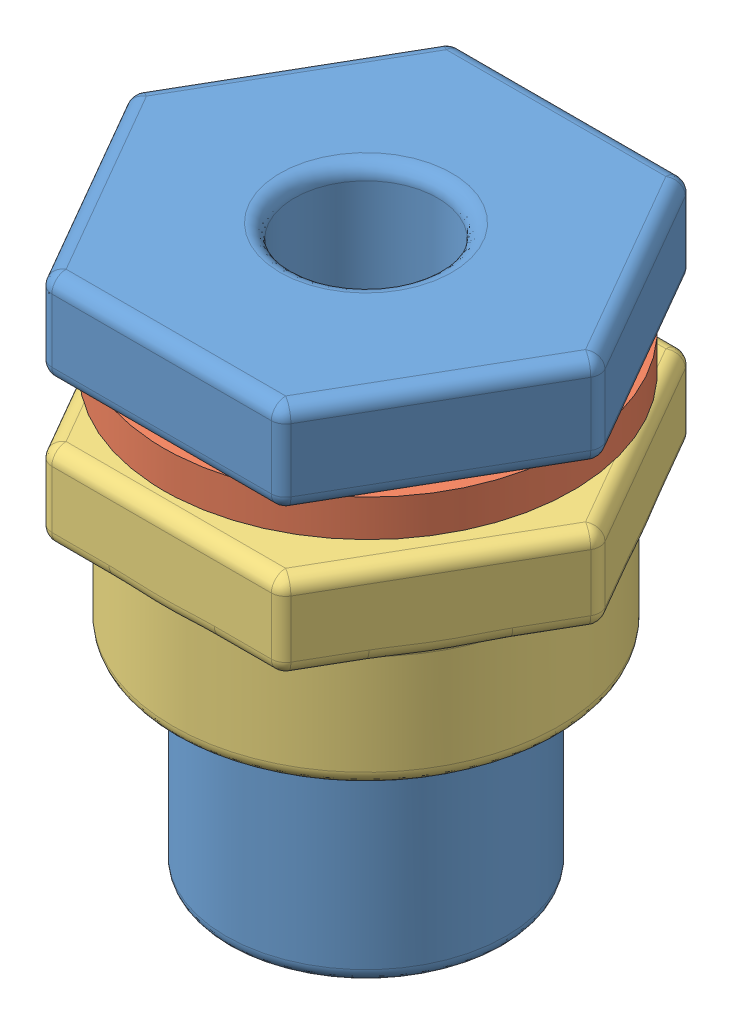
SolidWorks assembly drain_assembly, configuration Default. Lengths in mm.
Overall size (58.27 70.14 50.8).
3 component instances, 3 part files, 4 mates.
Components (placement in the parent):
- drain-1: drain [Default] at (3.4475 67.5493 60.8792) size (58.27 70.14 50.8)
- drain_gasket-1: drain_gasket [Default] at (3.4475 62.9773 60.8792) size (50.8 4.57 50.8)
- drain_nut-1: drain_nut [Default] at (3.4475 60.4373 60.8792) x (-1 0 0) z (0 0 1) size (58.11 25.4 50.8)
Mates (geometry in assembly coordinates):
- Concentric1: concentric anti-aligned: circle of drain-1; circle of drain_gasket-1
- Concentric2: concentric anti-aligned: circle of drain-1; circle of drain_nut-1
- Coincident2: coincident anti-aligned: plane of drain-1 through (3.4475 67.5493 60.8792) normal (0 -1 0); plane of drain_gasket-1 through (3.7157 67.5493 60.8792) normal (0 1 0)
- Distance1: distance = 2.54 mm anti-aligned: plane of drain_nut-1 through (3.4475 60.4373 60.8792) normal (0 1 0); plane of drain_gasket-1 through (3.7157 62.9773 60.8792) normal (0 -1 0)
